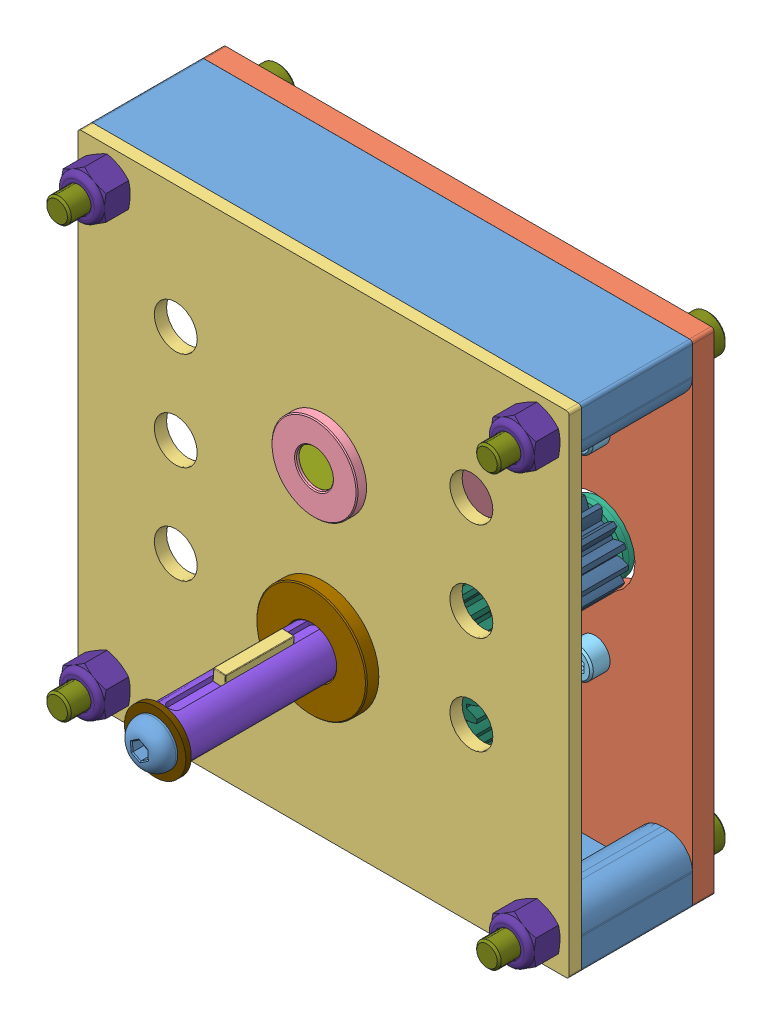
SolidWorks assembly am-0145+Updated+Toughbox+2015, configuration Default. Lengths in mm.
Overall size (127.03 127 97.81).
39 component instances, 21 part files, 0 mates.
Components (placement in the parent):
- am-2650 TB Spacer-1: am-2650 TB Spacer [Default] at (-20.7449 79.3887 80.3249) size (127 14.35 28.75)
- am-0155 Toughbox Motor Plate-1: am-0155 Toughbox Motor Plate [Default] at (21.1445 38.6364 74.7369) x (1 0 0) z (0 1 0) size (127 5.59 127)
- am-2650 TB Spacer-2: am-2650 TB Spacer [Default] at (90.4055 -31.7363 80.3249) x (-1 0 0) z (0 0 1) size (127 14.35 28.75)
- Toughbox d02 am-0261-1: Toughbox d02 am-0261 [Default] at (21.1699 38.6364 109.0777) x (1 0 0) z (0 1 0) size (127 3.17 127)
- FR6ZZ Bearing-1: FR6ZZ Bearing [Default] at (40.6889 12.4563 81.8489) x (0.923728 0.383049 0) z (0 0 -1) size (24.69 24.69 7.16)
- FR6ZZ Bearing-2: FR6ZZ Bearing [Default] at (40.6889 53.1471 81.8489) x (0.923728 0.383049 0) z (0 0 -1) size (24.69 24.69 7.16)
- 10-32x0500_shcs_HX-SHCS 0.19-32x1.375x1-C-1: 10-32x0500_shcs_HX-SHCS 0.19-32x1.375x1-C [Default] at (-3.3906 4.7762 85.1509) x (0 0 -1) z (1 0 0) size (17.53 7.94 7.94)
- 10-32x0500_shcs_HX-SHCS 0.19-32x1.375x1-C-2: 10-32x0500_shcs_HX-SHCS 0.19-32x1.375x1-C [Default] at (-3.3906 55.5762 85.1509) x (0 0 -1) z (1 0 0) size (17.53 7.94 7.94)
- 10-32x0500_shcs_HX-SHCS 0.19-32x1.375x1-C-3: 10-32x0500_shcs_HX-SHCS 0.19-32x1.375x1-C [Default] at (73.0258 55.5762 85.1509) x (0 0 -1) z (1 0 0) size (17.53 7.94 7.94)
- 10-32x0500_shcs_HX-SHCS 0.19-32x1.375x1-C-4: 10-32x0500_shcs_HX-SHCS 0.19-32x1.375x1-C [Default] at (73.0258 4.7762 85.1509) x (0 0 -1) z (1 0 0) size (17.53 7.94 7.94)
- 5-16 washer-1: 5-16 washer [Default] at (-3.3906 30.1762 78.8009) size (17.53 17.53 1.47)
- 5-16 washer-2: 5-16 washer [Default] at (-3.3906 30.1762 80.2741) size (17.53 17.53 1.47)
- 5-16 washer-3: 5-16 washer [Default] at (73.0258 30.1762 78.8009) size (17.53 17.53 1.47)
- 5-16 washer-4: 5-16 washer [Default] at (73.0258 30.1762 80.2741) size (17.53 17.53 1.47)
- Toughbox Small Hex Shaft-1: Toughbox Small Hex Shaft [Default] at (34.8176 44.1716 75.8037) x (0.5 -0.866025 0) z (0 0 1) size (11 9.53 38.11)
- TB Output Shaft-1: TB Output Shaft [Default] at (-2.2613 22.7278 107.2489) x (-0.997664 0.068316 0) z (0.068316 0.997664 0) size (14.66 92.33 12.7)
- FR6ZZ Bearing-3: FR6ZZ Bearing [Default] at (43.7045 38.1296 107.5537) size (24.69 24.69 7.16)
- FR8ZZ Bearing-1: FR8ZZ Bearing [Default] at (43.7045 -2.5612 107.5029) size (31.75 31.75 7.95)
- 14T CIM Gear-1: 14T CIM Gear [Default] at (-3.3906 30.1762 81.7473) size (20.03 20.32 12.7)
- 14T CIM Gear-2: 14T CIM Gear [Default] at (73.0258 30.1762 81.7473) x (0.98536 0.170489 0) z (0 0 1) size (20.03 20.32 12.7)
- 8mm_spring_clip am-0033-1: 8mm_spring_clip am-0033 [Default] at (-3.3906 30.1762 94.4473) x (0 0 1) z (-1 0 0) size (1.12 14.83 14.83)
- 8mm_spring_clip am-0033-2: 8mm_spring_clip am-0033 [Default] at (73.0258 30.1762 94.4473) x (0 0 1) z (-1 0 0) size (1.12 14.83 14.83)
- 500-e-klip_smart-1: 500-e-klip_smart [Default] at (62.138 11.0174 96.4031) x (1 0 0) z (0 1 0) size (19.07 1.27 20.95)
- 50T 20dp 375hex_Inch - Spur gear 20DP 50T 14.5PA .372FW ---S50N3.0H2.0L0.25N-1: 50T 20dp 375hex_Inch - Spur gear 20DP 50T 14.5PA .372FW ---S50N3.0H2.0L0.25N [Default] at (34.8176 44.1716 92.0089) x (0 0 -1) z (1 0 0) size (10.16 65.97 66.04)
- 14T 20dp 375hex_Inch - Spur gear 20DP 14T 14.5PA .568FW ---S14N3.0H2.0L0.25N-1: 14T 20dp 375hex_Inch - Spur gear 20DP 14T 14.5PA .568FW ---S14N3.0H2.0L0.25N [Default] at (34.843 44.1716 92.0089) x (0 0 1) z (-1 0 0) size (15.14 19.97 20.32)
- 50T 20dp 500hex-1: 50T 20dp 500hex [Default] at (34.8176 3.4808 96.4031) x (0.997664 -0.068316 0) z (0 0 1) size (65.97 66.04 10.62)
- SHCS 14-20 x 2-1: SHCS 14-20 x 2 [Default] at (90.3801 79.3887 68.1837) x (1 0 0) z (0 1 0) size (9.53 57.35 9.53)
- SHCS 14-20 x 2-2: SHCS 14-20 x 2 [Default] at (-20.7449 79.3887 68.1837) x (1 0 0) z (0 1 0) size (9.53 57.35 9.53)
- SHCS 14-20 x 2-3: SHCS 14-20 x 2 [Default] at (-20.7449 -31.7363 68.1837) x (1 0 0) z (0 1 0) size (9.53 57.35 9.53)
- SHCS 14-20 x 2-4: SHCS 14-20 x 2 [Default] at (90.3801 -31.7363 68.1837) x (1 0 0) z (0 1 0) size (9.53 57.35 9.53)
- 14-20 Nylock Nut_97135A210-1: 14-20 Nylock Nut_97135A210 [Default] at (-20.7195 79.3887 112.2527) x (1 0 0) z (0 -1 0) size (11.11 8.13 12.83)
- 14-20 Nylock Nut_97135A210-2: 14-20 Nylock Nut_97135A210 [Default] at (-20.7195 -31.7363 112.2527) x (1 0 0) z (0 -1 0) size (11.11 8.13 12.83)
- 14-20 Nylock Nut_97135A210-3: 14-20 Nylock Nut_97135A210 [Default] at (90.4055 -31.7363 112.2527) x (1 0 0) z (0 -1 0) size (11.11 8.13 12.83)
- 14-20 Nylock Nut_97135A210-4: 14-20 Nylock Nut_97135A210 [Default] at (90.4055 79.3887 112.2527) x (1 0 0) z (0 -1 0) size (11.11 8.13 12.83)
- 0.25 Flat Washer_Preferred Wide FW 0.25-1: 0.25 Flat Washer_Preferred Wide FW 0.25 [Default] at (34.8176 3.4808 154.3659) x (0 0 -1) z (1 0 0) size (1.4 15.88 15.88)
- BHCS 14-20 x 0.5-1: BHCS 14-20 x 0.5 [Default] at (34.8176 3.4808 159.8269) x (0.554675 -0.832067 0) z (-0.832067 -0.554675 0) size (11.69 16.79 11.69)
- 2mm x 2mm x 10mm Machine Key_smart-1: 2mm x 2mm x 10mm Machine Key_smart [Default] at (-25.2074 30.9762 84.4473) x (0 0 1) z (0 -1 0) size (10 2 2)
- 2mm x 2mm x 10mm Machine Key_smart-2: 2mm x 2mm x 10mm Machine Key_smart [Default] at (79.0195 13.1317 84.4473) x (0 0 1) z (0.98536 0.170489 0) size (10 2 2)
- 125 x 124 x 700 Machine Key-1: 125 x 124 x 700 Machine Key [Default] at (33.4941 11.4893 125.5831) x (0 0 1) z (-0.997664 0.068316 0) size (17.78 3.17 3.17)
